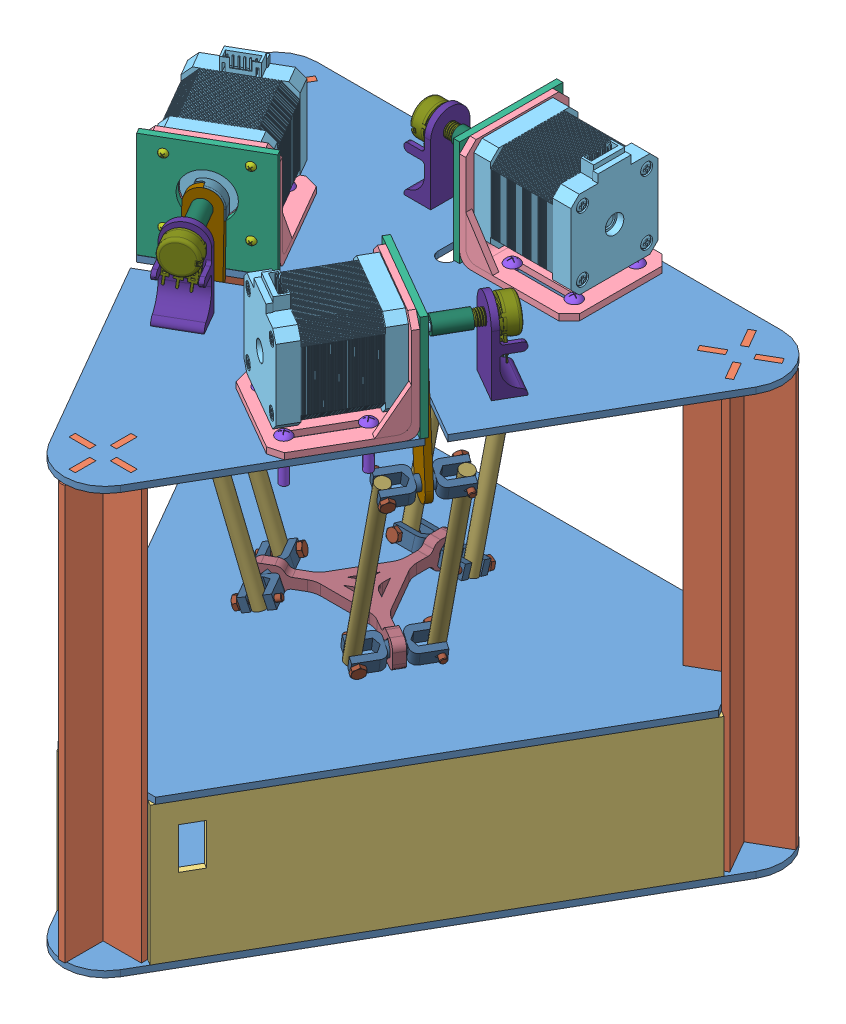
SolidWorks assembly Robot delta, configuration Predeterminado. Lengths in mm.
Overall size (336.1 262.3 347.14).
106 component instances, 19 part files, 66 mates.
Components (placement in the parent):
- Estructura Robot Delta-1: Estructura Robot Delta [Predeterminado] at origin size (336.1 206 347.14)
  - Base-4: Base [Base Superior] at (0 201.5 0) x (1 0 0) z (0 0 -1) size (265.17 3 235)
  - Pata-1: Pata [Predeterminado] at (-3.0521 78.0313 130.6393) size (40 206 40)
    - Pata-1: Pata [conf2] at (2.6829 -78.0313 0) size (3 206 40)
    - Pata-2: Pata [conf1] at (2.6829 -78.0313 0) x (0 0 -1) z (1 0 0) size (3 206 40)
  - Pieza1^Estructura Robot Delta-1: Pieza1^Estructura Robot Delta [Predeterminado] at origin (virtual)
  - Base-5: Base [Base Inferior] at (0 -1.5 0) x (0.5 0 -0.866025) z (0.866025 0 0.5) size (265.17 3 235)
  - Pata-4: Pata [Predeterminado] at (110.2598 78.0313 -63.6585) x (0.866025 0 -0.5) z (0.5 0 0.866025) size (40 206 40)
    - Pata-1: Pata [conf2] at (2.6829 -78.0313 0) size (3 206 40)
    - Pata-2: Pata [conf1] at (2.6829 -78.0313 0) x (0 0 -1) z (1 0 0) size (3 206 40)
  - Pata-5: Pata [Predeterminado] at (-114.663 78.0313 -62.6765) x (0.5 0 -0.866025) z (0.866025 0 0.5) size (40 206 40)
    - Pata-1: Pata [conf2] at (2.6829 -78.0313 0) size (3 206 40)
    - Pata-2: Pata [conf1] at (2.6829 -78.0313 0) x (0 0 -1) z (1 0 0) size (3 206 40)
  - Base-6: Base [base intermedia] at (0 68.5 0) x (1 0 0) z (0 0 -1) size (246.9 3 214.14)
  - Pared-1: Pared [Predeterminado] at (73.4268 33.5 42.8211) x (0.5 0 -0.866025) z (0.866025 0 0.5) size (203.31 67 3)
  - Pared-2: Pared [Predeterminado] at (0.1767 33.5 -85) x (-1 0 0) z (0 0 -1) size (203.31 67 3)
  - Pared-3: Pared [trasera] at (-73.613 33.5 42.4986) x (0.5 0 0.866025) z (-0.866025 0 0.5) size (203.31 67 3)
- Motor con base-1: Motor con base [Predeterminado] at (59.9895 228.5 -69.411) x (1 0 0) z (0 1 0) size (70.5 50 73.3)
  - soporte-1: soporte [Predeterminado] at (-53.4895 15.589 -25.5) size (53 50 51)
  - Nema17-1: Nema17 [Default] at (-3.4895 -9.411 3.5) x (0 0 1) z (0 -1 0) size (48.4 67.5 42.2)
  - Cara motor-1: Cara motor [Predeterminado] at (-53.4895 15.589 -25.5) x (0 0 1) z (-1 0 0) size (51 50 3)
  - M3_10mm-1: M3_10mm [Predeterminado] at (-46.4895 -24.911 19) x (0 -0.647004 -0.762487) z (1 0 0) size (4 4 11.5)
  - M3_10mm-2: M3_10mm [Predeterminado] at (-46.4895 6.2099 18.8791) x (0 -0.762487 0.647004) z (1 0 0) size (4 4 11.5)
  - M3_10mm-3: M3_10mm [Predeterminado] at (-46.4895 6.089 -12.2418) x (0 0.647004 0.762487) z (1 0 0) size (4 4 11.5)
  - M3_10mm-4: M3_10mm [Predeterminado] at (-46.4895 -25.0319 -12.1209) x (0 0.762487 -0.647004) z (1 0 0) size (4 4 11.5)
  - M4_20mm-1: M4_20mm [Predeterminado] at (-7.9895 -24.411 -42.5) x (0.921394 -0.38863 0) z (0 0 -1) size (7 7 22)
  - M4_20mm-2: M4_20mm [Predeterminado] at (-37.9895 -24.411 -42.5) x (0.921394 -0.38863 0) z (0 0 -1) size (7 7 22)
  - M4_20mm-3: M4_20mm [Predeterminado] at (-7.9895 5.589 -42.5) x (0.921394 -0.38863 0) z (0 0 -1) size (7 7 22)
  - M4_20mm-4: M4_20mm [Predeterminado] at (-37.9895 5.589 -42.5) x (0.921394 -0.38863 0) z (0 0 -1) size (7 7 22)
- Pieza1^Robot delta-1: Pieza1^Robot delta [Predeterminado] at origin (virtual)
- Eslabon-2: Eslabon [Predeterminado] at (0 232 -60) x (0 -0.108599 -0.994086) z (1 0 0) size (15 75 3)
- EjeDeRotacion-2: EjeDeRotacion [Predeterminado] at (-1 172.3549 -53.4841) x (0 0.288734 0.957409) z (1 0 0) size (18.2 6.9 36.12)
  - MedioEjeRotacion-1: MedioEjeRotacion [Predeterminado] at origin size (13 6.35 18.5)
  - MedioEjeRotacion-2: MedioEjeRotacion [Predeterminado] at (0 0 2.5) x (-1 0 0) z (0 0 -1) size (13 6.35 18.5)
  - bolt_gb_t_5783_m3x16-1: bolt_gb_t_5783_m3x16 [Default] at (-6.9 0 -13.75) x (1 0 0) z (0 0.098753 0.995112) size (18 6.35 5.5)
  - bolt_gb_t_5783_m3x16-2: bolt_gb_t_5783_m3x16 [Default] at (6.9 0 16.25) x (-1 0 0) z (0 0.106123 0.994353) size (18 6.35 5.5)
- eje-1: eje [1-4] at (17.5408 129.3273 -40.5079) x (0 -0.288734 -0.957409) z (0.998703 0.048739 -0.014699) size (6.35 96 6.35)
- eje-2: eje [1-4] at (-12.4592 129.3273 -40.5079) x (0 -0.288734 -0.957409) z (0.998703 0.048739 -0.014699) size (6.35 96 6.35)
- EjeDeRotacion-3: EjeDeRotacion [Predeterminado] at (3.5816 86.2998 -27.5317) x (0 -0.288734 -0.957409) z (1 0 0) size (18.2 6.9 36.12)
  - MedioEjeRotacion-1: MedioEjeRotacion [Predeterminado] at origin size (13 6.35 18.5)
  - MedioEjeRotacion-2: MedioEjeRotacion [Predeterminado] at (0 0 2.5) x (-1 0 0) z (0 0 -1) size (13 6.35 18.5)
  - bolt_gb_t_5783_m3x16-1: bolt_gb_t_5783_m3x16 [Default] at (-6.9 0 -13.75) x (1 0 0) z (0 0.098753 0.995112) size (18 6.35 5.5)
  - bolt_gb_t_5783_m3x16-2: bolt_gb_t_5783_m3x16 [Default] at (6.9 0 16.25) x (-1 0 0) z (0 0.106123 0.994353) size (18 6.35 5.5)
- Motor con base-4: Motor con base [Predeterminado] at (-90.0744 228.5 -17.2651) x (-0.5 0 -0.866025) z (0 1 0) size (70.5 50 73.3)
  - soporte-1: soporte [Predeterminado] at (-53.4895 15.589 -25.5) size (53 50 51)
  - Nema17-1: Nema17 [Default] at (-3.4895 -9.411 3.5) x (0 0 1) z (0 -1 0) size (48.4 67.5 42.2)
  - Cara motor-1: Cara motor [Predeterminado] at (-53.4895 15.589 -25.5) x (0 0 1) z (-1 0 0) size (51 50 3)
  - M3_10mm-1: M3_10mm [Predeterminado] at (-46.4895 -24.911 19) x (0 -0.647004 -0.762487) z (1 0 0) size (4 4 11.5)
  - M3_10mm-2: M3_10mm [Predeterminado] at (-46.4895 6.2099 18.8791) x (0 -0.762487 0.647004) z (1 0 0) size (4 4 11.5)
  - M3_10mm-3: M3_10mm [Predeterminado] at (-46.4895 6.089 -12.2418) x (0 0.647004 0.762487) z (1 0 0) size (4 4 11.5)
  - M3_10mm-4: M3_10mm [Predeterminado] at (-46.4895 -25.0319 -12.1209) x (0 0.762487 -0.647004) z (1 0 0) size (4 4 11.5)
  - M4_20mm-1: M4_20mm [Predeterminado] at (-7.9895 -24.411 -42.5) x (0.921394 -0.38863 0) z (0 0 -1) size (7 7 22)
  - M4_20mm-2: M4_20mm [Predeterminado] at (-37.9895 -24.411 -42.5) x (0.921394 -0.38863 0) z (0 0 -1) size (7 7 22)
  - M4_20mm-3: M4_20mm [Predeterminado] at (-7.9895 5.589 -42.5) x (0.921394 -0.38863 0) z (0 0 -1) size (7 7 22)
  - M4_20mm-4: M4_20mm [Predeterminado] at (-37.9895 5.589 -42.5) x (0.921394 -0.38863 0) z (0 0 -1) size (7 7 22)
- Motor con base-5: Motor con base [Predeterminado] at (30.1172 228.5 86.621) x (-0.5 0 0.866025) z (0 1 0) size (70.5 50 73.3)
  - soporte-1: soporte [Predeterminado] at (-53.4895 15.589 -25.5) size (53 50 51)
  - Nema17-1: Nema17 [Default] at (-3.4895 -9.411 3.5) x (0 0 1) z (0 -1 0) size (48.4 67.5 42.2)
  - Cara motor-1: Cara motor [Predeterminado] at (-53.4895 15.589 -25.5) x (0 0 1) z (-1 0 0) size (51 50 3)
  - M3_10mm-1: M3_10mm [Predeterminado] at (-46.4895 -24.911 19) x (0 -0.647004 -0.762487) z (1 0 0) size (4 4 11.5)
  - M3_10mm-2: M3_10mm [Predeterminado] at (-46.4895 6.2099 18.8791) x (0 -0.762487 0.647004) z (1 0 0) size (4 4 11.5)
  - M3_10mm-3: M3_10mm [Predeterminado] at (-46.4895 6.089 -12.2418) x (0 0.647004 0.762487) z (1 0 0) size (4 4 11.5)
  - M3_10mm-4: M3_10mm [Predeterminado] at (-46.4895 -25.0319 -12.1209) x (0 0.762487 -0.647004) z (1 0 0) size (4 4 11.5)
  - M4_20mm-1: M4_20mm [Predeterminado] at (-7.9895 -24.411 -42.5) x (0.921394 -0.38863 0) z (0 0 -1) size (7 7 22)
  - M4_20mm-2: M4_20mm [Predeterminado] at (-37.9895 -24.411 -42.5) x (0.921394 -0.38863 0) z (0 0 -1) size (7 7 22)
  - M4_20mm-3: M4_20mm [Predeterminado] at (-7.9895 5.589 -42.5) x (0.921394 -0.38863 0) z (0 0 -1) size (7 7 22)
  - M4_20mm-4: M4_20mm [Predeterminado] at (-37.9895 5.589 -42.5) x (0.921394 -0.38863 0) z (0 0 -1) size (7 7 22)
- Efector final-1: Efector final [Predeterminado] at (4.8316 86.2998 7.4683) size (74.12 12.7 64.19)
- Eslabon-3: Eslabon [Predeterminado] at (51.6529 232 30.498) x (0.857674 0.138545 0.495178) z (-0.5 0 0.866025) size (15 75 3)
- Eslabon-4: Eslabon [Predeterminado] at (-51.621 232 30.5161) x (0.865952 -0.013055 -0.499957) z (0.5 0 0.866025) size (15 75 3)
- EjeDeRotacion-4: EjeDeRotacion [Predeterminado] at (-52.9243 172.0051 29.8252) x (0.828201 0.292308 -0.478162) z (0.5 0 0.866025) size (18.2 6.9 36.12)
  - MedioEjeRotacion-1: MedioEjeRotacion [Predeterminado] at origin size (13 6.35 18.5)
  - MedioEjeRotacion-2: MedioEjeRotacion [Predeterminado] at (0 0 2.5) x (-1 0 0) z (0 0 -1) size (13 6.35 18.5)
  - bolt_gb_t_5783_m3x16-1: bolt_gb_t_5783_m3x16 [Default] at (-6.9 0 -13.75) x (1 0 0) z (0 0.098753 0.995112) size (18 6.35 5.5)
  - bolt_gb_t_5783_m3x16-2: bolt_gb_t_5783_m3x16 [Default] at (6.9 0 16.25) x (-1 0 0) z (0 0.106123 0.994353) size (18 6.35 5.5)
- eje-3: eje [1-4] at (-46.3893 129.1524 14.9477) x (0.828201 0.292308 -0.478162) z (0.474635 0.087837 0.875789) size (6.35 96 6.35)
- eje-4: eje [1-4] at (-31.3893 129.1524 40.9284) x (0.828201 0.292308 -0.478162) z (0.474635 0.087837 0.875789) size (6.35 96 6.35)
- EjeDeRotacion-5: EjeDeRotacion [Predeterminado] at (-26.1043 86.2998 23.8858) x (-0.828201 -0.292308 0.478162) z (0.5 0 0.866025) size (18.2 6.9 36.12)
  - MedioEjeRotacion-1: MedioEjeRotacion [Predeterminado] at origin size (13 6.35 18.5)
  - MedioEjeRotacion-2: MedioEjeRotacion [Predeterminado] at (0 0 2.5) x (-1 0 0) z (0 0 -1) size (13 6.35 18.5)
  - bolt_gb_t_5783_m3x16-1: bolt_gb_t_5783_m3x16 [Default] at (-6.9 0 -13.75) x (1 0 0) z (0 0.098753 0.995112) size (18 6.35 5.5)
  - bolt_gb_t_5783_m3x16-2: bolt_gb_t_5783_m3x16 [Default] at (6.9 0 16.25) x (-1 0 0) z (0 0.106123 0.994353) size (18 6.35 5.5)
- Seguidor_Eslabon-2: Seguidor_Eslabon [Predeterminado] at (49.9029 232 33.5291) x (-0.866025 0 -0.5) z (0.5 0 -0.866025) size (12.25 13.15 5.26)
- EjeDeRotacion-6: EjeDeRotacion [Predeterminado] at (59.4769 172.5786 33.5718) x (0.830835 -0.282165 0.479683) z (-0.5 0 0.866025) size (18.2 6.9 36.12)
  - MedioEjeRotacion-1: MedioEjeRotacion [Predeterminado] at origin size (13 6.35 18.5)
  - MedioEjeRotacion-2: MedioEjeRotacion [Predeterminado] at (0 0 2.5) x (-1 0 0) z (0 0 -1) size (13 6.35 18.5)
  - bolt_gb_t_5783_m3x16-1: bolt_gb_t_5783_m3x16 [Default] at (-6.9 0 -13.75) x (1 0 0) z (0 0.098753 0.995112) size (18 6.35 5.5)
  - bolt_gb_t_5783_m3x16-2: bolt_gb_t_5783_m3x16 [Default] at (6.9 0 16.25) x (-1 0 0) z (0 0.106123 0.994353) size (18 6.35 5.5)
- EjeDeRotacion-7: EjeDeRotacion [Predeterminado] at (35.7675 86.2998 23.8858) x (0.830835 -0.282165 0.479683) z (-0.5 0 0.866025) size (18.2 6.9 36.12)
  - MedioEjeRotacion-1: MedioEjeRotacion [Predeterminado] at origin size (13 6.35 18.5)
  - MedioEjeRotacion-2: MedioEjeRotacion [Predeterminado] at (0 0 2.5) x (-1 0 0) z (0 0 -1) size (13 6.35 18.5)
  - bolt_gb_t_5783_m3x16-1: bolt_gb_t_5783_m3x16 [Default] at (-6.9 0 -13.75) x (1 0 0) z (0 0.098753 0.995112) size (18 6.35 5.5)
  - bolt_gb_t_5783_m3x16-2: bolt_gb_t_5783_m3x16 [Default] at (6.9 0 16.25) x (-1 0 0) z (0 0.106123 0.994353) size (18 6.35 5.5)
- eje-5: eje [1-4] at (39.4972 129.4392 42.8017) x (0.830835 -0.282165 0.479683) z (-0.490217 0.036951 0.870817) size (6.35 96 6.35)
- eje-6: eje [1-4] at (54.4972 129.4392 16.8209) x (0.830835 -0.282165 0.479683) z (-0.490217 0.036951 0.870817) size (6.35 96 6.35)
- Conector_Pot_Motor-1: Conector_Pot_Motor [Predeterminado] at (57.4617 232 20.4369) x (0.866025 0 0.5) z (-0.5 0 0.866025) size (8 8 15)
- POT_WH148_15MM-1: POT_WH148_15MM [Default] at (66.4317 232 4.9004) x (0.859764 0.12003 0.496385) z (0.103949 -0.99277 0.060015) size (16.35 23.93 24.85)
- Base pot-1: Base pot [Predeterminado] at (63.4617 232 10.0446) x (-0.866025 0 -0.5) z (0.5 0 -0.866025) size (19 38.5 13)
- POT_WH148_15MM-2: POT_WH148_15MM [Default] at (-28.94 232 -60) x (0 0.12003 -0.99277) z (0 -0.99277 -0.12003) size (16.35 23.93 24.85)
- POT_WH148_15MM-3: POT_WH148_15MM [Default] at (-37.4595 232 55.0445) x (-0.859764 0.12003 0.496385) z (-0.103949 -0.99277 0.060015) size (16.35 23.93 24.85)
- Base pot-2: Base pot [Predeterminado] at (-23 232 -60) x (0 0 1) z (-1 0 0) size (19 38.5 13)
- Base pot-3: Base pot [Predeterminado] at (-40.4295 232 49.9003) x (0.866025 0 -0.5) z (0.5 0 0.866025) size (19 38.5 13)
- Conector_Pot_Motor-2: Conector_Pot_Motor [Predeterminado] at (-11 232 -60) x (0 0 -1) z (1 0 0) size (8 8 15)
- Conector_Pot_Motor-3: Conector_Pot_Motor [Predeterminado] at (-46.4295 232 39.508) x (-0.866025 0 0.5) z (-0.5 0 -0.866025) size (8 8 15)
- Seguidor_Eslabon-3: Seguidor_Eslabon [Predeterminado] at (-53.371 232 27.485) x (0.865952 -0.013055 -0.499957) z (0.5 0 0.866025) size (12.25 13.15 5.26)
- Seguidor_Eslabon-4: Seguidor_Eslabon [Predeterminado] at (3.5 232 -60) x (0 0.108599 0.994086) z (-1 0 0) size (12.25 13.15 5.26)
Mates (geometry in assembly coordinates):
- Concéntrica3: concentric aligned: cylinder of Motor con base-1/Nema17-1 through (-11 232 -60) axis (1 0 0) radius 2.5; cylinder of Eslabon-2 through (-1.5 232 -60) axis (1 0 0) radius 2.5
- Concéntrica4: concentric aligned: cylinder of Eslabon-2 through (-1.5 172.3549 -53.4841) axis (1 0 0) radius 3.175; cylinder of EjeDeRotacion-2/MedioEjeRotacion-2 through (-3.5 172.3549 -53.4841) axis (1 0 0) radius 3.175
- Coincidente21: coincident anti-aligned: plane of Eslabon-2 through (1.5 232 -60) normal (1 0 0); circle of EjeDeRotacion-2/MedioEjeRotacion-2
- Concéntrica5: concentric aligned: cylinder of EjeDeRotacion-2/07161-104x25-1 through (15.25 219.0944 -64.6309) axis (0 0.377584 -0.925975) radius 2; cylinder of eje-1 through (15.25 173.2716 -50.4443) axis (0 -0.288734 -0.957409) radius 1.5
- Coincidente23: coincident anti-aligned: plane of EjeDeRotacion-2 through (-1 172.3549 -53.4841) normal (0 0.288734 0.957409); plane of eje-1 through (17.5408 129.3273 -40.5079) normal (0 -0.288734 -0.957409)
- Concéntrica6: concentric anti-aligned: cylinder of EjeDeRotacion-2/07161-104x25-2 through (-14.75 234.1977 -101.6699) axis (0 -0.377584 0.925975) radius 2; cylinder of eje-2 through (-14.75 173.2716 -50.4443) axis (0 -0.288734 -0.957409) radius 1.5
- Coincidente24: coincident anti-aligned: plane of EjeDeRotacion-2 through (-1 172.3549 -53.4841) normal (0 0.288734 0.957409); plane of eje-2 through (-12.4592 129.3273 -40.5079) normal (0 -0.288734 -0.957409)
- Concéntrica7: concentric anti-aligned: cylinder of eje-1 through (19.8316 87.2165 -24.4919) axis (0 -0.288734 -0.957409) radius 1.5; cylinder of EjeDeRotacion-3/07161-104x25-1 through (7.1588 151.1975 -135.5149) axis (0 -0.377584 0.925975) radius 2
- Concéntrica8: concentric aligned: cylinder of eje-2 through (-10.1684 87.2165 -24.4919) axis (0 -0.288734 -0.957409) radius 1.5; cylinder of EjeDeRotacion-3/07161-104x25-2 through (-22.8412 136.0941 -98.4759) axis (0 0.377584 -0.925975) radius 2
- Coincidente25: coincident anti-aligned: plane of EjeDeRotacion-2 through (-1 172.3549 -53.4841) normal (0 0.288734 0.957409); plane of EjeDeRotacion-3 through (3.5816 86.2998 -27.5317) normal (0 -0.288734 -0.957409)
- Coincidente27: coincident anti-aligned: plane of Estructura Robot Delta-1/Base-4 through (-112.5833 203 -65) normal (0 1 0); plane of Motor con base-1/soporte-1 through (11.5 203 -85) normal (0 -1 0)
- Coincidente32: coincident aligned: plane of Estructura Robot Delta-1/Base-4 through (22 203.001 -47.1) normal (0 0 1); plane of Motor con base-1/soporte-1 through (52 206 -47.1) normal (0 0 1)
- Concéntrica12: concentric anti-aligned: cylinder of Estructura Robot Delta-1/Base-4 through (22 203.001 -45) axis (0 -1 0) radius 2.1; cylinder of Motor con base-1/soporte-1 through (22 206 -45) axis (0 1 0) radius 2.1
- Coincidente33: coincident: point of Estructura Robot Delta-1/Base-4; plane of Eslabon-2 through (0 232 -60) normal (1 0 0)
- Concéntrica13: concentric aligned: cylinder of EjeDeRotacion-3/MedioEjeRotacion-2 through (1.0816 86.2998 -27.5317) axis (1 0 0) radius 3.175; cylinder of Efector final-1 through (-21.231 86.2998 -27.5317) axis (1 0 0) radius 3.175
- Concéntrica14: concentric aligned: cylinder of Motor con base-5/Nema17-1 through (57.4617 232 20.4369) axis (-0.5 0 0.866025) radius 2.5; cylinder of Eslabon-3 through (52.4029 232 29.1989) axis (-0.5 0 0.866025) radius 2.5
- Coincidente35: coincident: unknown of Estructura Robot Delta-1/Base-4; plane of Eslabon-3 through (51.6529 232 30.498) normal (-0.5 0 0.866025)
- Concéntrica15: concentric anti-aligned: cylinder of Motor con base-4/Nema17-1 through (-46.4295 232 39.508) axis (-0.5 0 -0.866025) radius 2.5; cylinder of Eslabon-4 through (-52.371 232 29.2171) axis (0.5 0 0.866025) radius 2.5
- Coincidente36: coincident: unknown of Estructura Robot Delta-1/Base-4; plane of Eslabon-4 through (-51.621 232 30.5161) normal (0.5 0 0.866025)
- Concéntrica16: concentric aligned: cylinder of Eslabon-4 through (-53.0493 172.0051 29.6087) axis (0.5 0 0.866025) radius 3.175; cylinder of EjeDeRotacion-4/MedioEjeRotacion-2 through (-54.1743 172.0051 27.6601) axis (0.5 0 0.866025) radius 3.175
- Paralelo1: parallel anti-aligned: plane of Estructura Robot Delta-1/Base-4 through (-112.5833 200 -65) normal (0 -1 0); plane of Efector final-1 through (17.3316 88.7998 -13.381) normal (0 1 0)
- Concéntrica17: concentric anti-aligned: cylinder of eje-2 through (-10.1684 87.2165 -24.4919) axis (0 -0.288734 -0.957409) radius 1.5; cylinder of EjeDeRotacion-3/bolt_gb_t_5783_m3x16-1 through (-10.1684 85.949 -28.6946) axis (0 0.288734 0.957409) radius 1.5
- Concéntrica18: concentric aligned: cylinder of eje-1 through (19.8316 87.2165 -24.4919) axis (0 -0.288734 -0.957409) radius 1.5; cylinder of EjeDeRotacion-3/bolt_gb_t_5783_m3x16-2 through (19.8316 86.6505 -26.3687) axis (0 -0.288734 -0.957409) radius 1.5
- Concéntrica19: concentric anti-aligned: cylinder of EjeDeRotacion-2/bolt_gb_t_5783_m3x16-2 through (15.25 172.0041 -54.647) axis (0 0.288734 0.957409) radius 1.5; cylinder of eje-1 through (15.25 173.2716 -50.4443) axis (0 -0.288734 -0.957409) radius 1.5
- Concéntrica20: concentric aligned: cylinder of EjeDeRotacion-2/bolt_gb_t_5783_m3x16-1 through (-14.75 172.7056 -52.3211) axis (0 -0.288734 -0.957409) radius 1.5; cylinder of eje-2 through (-14.75 173.2716 -50.4443) axis (0 -0.288734 -0.957409) radius 1.5
- Concéntrica21: concentric anti-aligned: cylinder of EjeDeRotacion-4/bolt_gb_t_5783_m3x16-1 through (-58.7933 172.3602 17.3365) axis (-0.828201 -0.292308 0.478162) radius 1.5; cylinder of eje-3 through (-62.4289 171.077 19.4355) axis (0.828201 0.292308 -0.478162) radius 1.5
- Concéntrica22: concentric aligned: cylinder of EjeDeRotacion-4/bolt_gb_t_5783_m3x16-2 through (-45.8053 171.65 44.4789) axis (0.828201 0.292308 -0.478162) radius 1.5; cylinder of eje-4 through (-47.4289 171.077 45.4163) axis (0.828201 0.292308 -0.478162) radius 1.5
- Coincidente37: coincident aligned: plane of EjeDeRotacion-4 through (-52.9243 172.0051 29.8252) normal (0.828201 0.292308 -0.478162); plane of eje-3 through (-46.3893 129.1524 14.9477) normal (0.828201 0.292308 -0.478162)
- Coincidente38: coincident aligned: plane of EjeDeRotacion-4 through (-52.9243 172.0051 29.8252) normal (0.828201 0.292308 -0.478162); plane of eje-4 through (-31.3893 129.1524 40.9284) normal (0.828201 0.292308 -0.478162)
- Concéntrica26: concentric anti-aligned: cylinder of eje-4 through (-20.6088 85.3717 39.4769) axis (0.828201 0.292308 -0.478162) radius 1.5; cylinder of EjeDeRotacion-5/bolt_gb_t_5783_m3x16-2 through (-16.9733 86.6548 37.3779) axis (-0.828201 -0.292308 0.478162) radius 1.5
- Concéntrica27: concentric aligned: cylinder of eje-3 through (-35.6088 85.3717 13.4961) axis (0.828201 0.292308 -0.478162) radius 1.5; cylinder of EjeDeRotacion-5/bolt_gb_t_5783_m3x16-1 through (-33.9853 85.9447 12.5588) axis (0.828201 0.292308 -0.478162) radius 1.5
- Coincidente39: coincident anti-aligned: plane of EjeDeRotacion-4 through (-52.9243 172.0051 29.8252) normal (0.828201 0.292308 -0.478162); plane of EjeDeRotacion-5 through (-26.1043 86.2998 23.8858) normal (-0.828201 -0.292308 0.478162)
- Concéntrica33: concentric anti-aligned: cylinder of Motor con base-5/Nema17-1 through (57.4617 232 20.4369) axis (-0.5 0 0.866025) radius 2.5; cylinder of Seguidor_Eslabon-2 through (49.9024 232 33.5299) axis (0.5 0 -0.866025) radius 2.6
- Paralelo3: parallel anti-aligned: plane of Motor con base-5/Nema17-1 through (48.9617 234 35.1593) normal (0 1 0); plane of Seguidor_Eslabon-2 through (51.23 234.1 34.2964) normal (0 -1 0)
- Coincidente47: coincident anti-aligned: plane of Eslabon-3 through (50.9029 232 31.797) normal (-0.5 0 0.866025); plane of Seguidor_Eslabon-2 through (50.9029 232 31.797) normal (0.5 0 -0.866025)
- Concéntrica34: concentric aligned: cylinder of Efector final-1 through (-6.3235 86.2998 58.1471) axis (-0.5 0 -0.866025) radius 3.175; cylinder of EjeDeRotacion-5/MedioEjeRotacion-1 through (-23.6043 86.2998 28.2159) axis (-0.5 0 -0.866025) radius 3.175
- Ancho1: width anti-aligned: plane of EjeDeRotacion-5/MedioEjeRotacion-2 through (-27.3543 86.2998 21.7207) normal (0.5 0 0.866025); plane of Efector final-1 through (-23.6043 86.2998 28.2159) normal (-0.5 0 -0.866025); plane of EjeDeRotacion-5/MedioEjeRotacion-1 through (-21.23 88.7998 19.6283) normal (-0.5 0 -0.866025); plane of Efector final-1 through (-11.9745 88.7998 20.0581) normal (0.5 0 0.866025)
- Concéntrica35: concentric anti-aligned: cylinder of EjeDeRotacion-3/MedioEjeRotacion-1 through (8.5816 86.2998 -27.5317) axis (-1 0 0) radius 3.175; cylinder of Efector final-1 through (-21.231 86.2998 -27.5317) axis (1 0 0) radius 3.175
- Ancho2: width aligned: plane of EjeDeRotacion-3/MedioEjeRotacion-1 through (8.5816 86.2998 -27.5317) normal (-1 0 0); plane of Efector final-1 through (1.0816 86.2998 -27.5317) normal (1 0 0); plane of EjeDeRotacion-3/MedioEjeRotacion-2 through (2.3316 88.7998 -13.381) normal (-1 0 0); plane of Efector final-1 through (7.3316 88.7998 -21.1817) normal (1 0 0)
- Concéntrica36: concentric anti-aligned: cylinder of Efector final-1 through (62.3133 86.2998 -22.0929) axis (-0.5 0 0.866025) radius 3.175; cylinder of EjeDeRotacion-7/MedioEjeRotacion-1 through (33.2675 86.2998 28.2159) axis (0.5 0 -0.866025) radius 3.175
- Ancho3: width anti-aligned: plane of EjeDeRotacion-7/MedioEjeRotacion-1 through (33.2675 86.2998 28.2159) normal (0.5 0 -0.866025); plane of Efector final-1 through (37.0175 86.2998 21.7207) normal (-0.5 0 0.866025); plane of EjeDeRotacion-7/MedioEjeRotacion-2 through (28.3932 88.7998 23.9584) normal (-0.5 0 0.866025); plane of Efector final-1 through (24.1377 88.7998 15.728) normal (0.5 0 -0.866025)
- Ancho4: width aligned: plane of EjeDeRotacion-6/MedioEjeRotacion-2 through (60.7269 172.5786 31.4067) normal (-0.5 0 0.866025); plane of Eslabon-3 through (56.9769 172.5786 37.9019) normal (0.5 0 -0.866025); plane of EjeDeRotacion-6/MedioEjeRotacion-1 through (50.9029 232 31.797) normal (-0.5 0 0.866025); plane of Eslabon-3 through (52.4029 232 29.1989) normal (0.5 0 -0.866025)
- Concéntrica37: concentric anti-aligned: cylinder of Eslabon-3 through (59.6019 172.5786 33.3553) axis (-0.5 0 0.866025) radius 3.175; cylinder of EjeDeRotacion-6/MedioEjeRotacion-1 through (56.9769 172.5786 37.9019) axis (0.5 0 -0.866025) radius 3.175
- Ancho5: width aligned: plane of EjeDeRotacion-4/MedioEjeRotacion-1 through (-50.4243 172.0051 34.1553) normal (-0.5 0 -0.866025); plane of Eslabon-4 through (-54.1743 172.0051 27.6601) normal (0.5 0 0.866025); plane of EjeDeRotacion-4/MedioEjeRotacion-2 through (-52.371 232 29.2171) normal (-0.5 0 -0.866025); plane of Eslabon-4 through (-50.871 232 31.8151) normal (0.5 0 0.866025)
- Coincidente48: coincident aligned: plane of EjeDeRotacion-6 through (59.4769 172.5786 33.5718) normal (0.830835 -0.282165 0.479683); plane of EjeDeRotacion-7 through (35.7675 86.2998 23.8858) normal (0.830835 -0.282165 0.479683)
- Concéntrica40: concentric aligned: cylinder of EjeDeRotacion-6/bolt_gb_t_5783_m3x16-2 through (50.3427 172.9214 47.062) axis (0.830835 -0.282165 0.479683) radius 1.5; cylinder of eje-5 through (48.714 173.4745 46.1217) axis (0.830835 -0.282165 0.479683) radius 1.5
- Concéntrica41: concentric aligned: cylinder of EjeDeRotacion-7/bolt_gb_t_5783_m3x16-2 through (26.6333 86.6425 37.3761) axis (0.830835 -0.282165 0.479683) radius 1.5; cylinder of eje-5 through (25.0046 87.1956 36.4357) axis (0.830835 -0.282165 0.479683) radius 1.5
- Tangente1: tangent anti-aligned: plane of EjeDeRotacion-7/MedioEjeRotacion-1 through (23.1035 84.1487 37.9362) normal (0.830835 -0.282165 0.479683); cylinder of eje-5 through (52.1422 175.4546 47.9676) axis (-0.263438 -0.958654 -0.107622) radius 3.175
- Tangente2: tangent anti-aligned: plane of EjeDeRotacion-6/MedioEjeRotacion-1 through (46.8129 170.4276 47.6222) normal (0.830835 -0.282165 0.479683); cylinder of eje-5 through (52.1422 175.4546 47.9676) axis (-0.263438 -0.958654 -0.107622) radius 3.175
- Concéntrica43: concentric anti-aligned: cylinder of EjeDeRotacion-7/bolt_gb_t_5783_m3x16-1 through (43.6517 85.957 12.5606) axis (-0.830835 0.282165 -0.479683) radius 1.5; cylinder of eje-6 through (40.0046 87.1956 10.455) axis (0.830835 -0.282165 0.479683) radius 1.5
- Concéntrica44: concentric anti-aligned: cylinder of EjeDeRotacion-6/bolt_gb_t_5783_m3x16-1 through (67.3611 172.2359 22.2466) axis (-0.830835 0.282165 -0.479683) radius 1.5; cylinder of eje-6 through (63.714 173.4745 20.1409) axis (0.830835 -0.282165 0.479683) radius 1.5
- Tangente4: tangent anti-aligned: plane of EjeDeRotacion-7/MedioEjeRotacion-2 through (35.3535 84.1487 16.7186) normal (0.830835 -0.282165 0.479683); cylinder of eje-6 through (67.1422 175.4546 21.9868) axis (-0.263438 -0.958654 -0.107622) radius 3.175
- Tangente6: tangent anti-aligned: plane of EjeDeRotacion-6/MedioEjeRotacion-2 through (59.0629 170.4276 26.4046) normal (0.830835 -0.282165 0.479683); cylinder of eje-6 through (67.1422 175.4546 21.9868) axis (-0.263438 -0.958654 -0.107622) radius 3.175
- Concéntrica45: concentric aligned: cylinder of Motor con base-5/Nema17-1 through (57.4617 232 20.4369) axis (-0.5 0 0.866025) radius 2.5; cylinder of Conector_Pot_Motor-1 through (57.4617 232 20.4369) axis (-0.5 0 0.866025) radius 2.6
- Paralelo5: parallel anti-aligned: line of Motor con base-5/Nema17-1 through (56.1627 234 19.6869) axis (0.866025 0 0.5); line of Conector_Pot_Motor-1 through (55.0393 234.1 27.6985) axis (-0.866025 0 -0.5)
- Coincidente51: coincident anti-aligned: plane of Motor con base-5/Nema17-1 through (57.4617 232 20.4369) normal (0.5 0 -0.866025); plane of Conector_Pot_Motor-1 through (57.4617 232 20.4369) normal (-0.5 0 0.866025)
- Coincidente52: coincident anti-aligned: plane of Estructura Robot Delta-1/Base-4 through (-112.5833 203 -65) normal (0 1 0); plane of Base pot-1 through (73.189 203 12.1965) normal (0 -1 0)
- Concéntrica46: concentric anti-aligned: cylinder of Conector_Pot_Motor-1 through (53.7117 232 26.932) axis (0.5 0 -0.866025) radius 4; cylinder of Base pot-1 through (64.9617 232 7.4465) axis (-0.5 0 0.866025) radius 3.38
- Coincidente53: coincident anti-aligned: circle of POT_WH148_15MM-1; circle of Base pot-1
- Coincidente54: coincident anti-aligned: plane of Conector_Pot_Motor-1 through (57.4617 232 20.4369) normal (0.5 0 -0.866025); plane of POT_WH148_15MM-1 through (57.4617 232 20.4369) normal (-0.5 0 0.866025)
- Concéntrica47: concentric anti-aligned: cylinder of Motor con base-4/Nema17-1 through (-46.4295 232 39.508) axis (-0.5 0 -0.866025) radius 2.5; cylinder of Seguidor_Eslabon-3 through (-53.3715 232 27.4841) axis (0.5 0 0.866025) radius 2.6
- Coincidente55: coincident anti-aligned: plane of Eslabon-4 through (-52.371 232 29.2171) normal (-0.5 0 -0.866025); plane of Seguidor_Eslabon-3 through (-52.371 232 29.2171) normal (0.5 0 0.866025)
- Paralelo6: parallel aligned: line of Eslabon-4 through (-45.0547 171.9072 28.4571) axis (0.011306 0.999915 -0.006527); line of Seguidor_Eslabon-3 through (-45.0293 226.9077 27.8651) axis (0.011306 0.999915 -0.006527)
- Concéntrica48: concentric anti-aligned: cylinder of Motor con base-1/Nema17-1 through (-11 232 -60) axis (1 0 0) radius 2.5; cylinder of Seguidor_Eslabon-4 through (3.501 232 -60) axis (-1 0 0) radius 2.6
- Paralelo8: parallel anti-aligned: plane of Eslabon-2 through (-1.5 232.8145 -52.5444) normal (0 0.108599 0.994086); plane of Seguidor_Eslabon-4 through (-1.5 227.8006 -52.399) normal (0 -0.108599 -0.994086)
- Coincidente59: coincident anti-aligned: plane of Eslabon-2 through (1.5 232 -60) normal (1 0 0); plane of Seguidor_Eslabon-4 through (1.5 232 -60) normal (-1 0 0)
